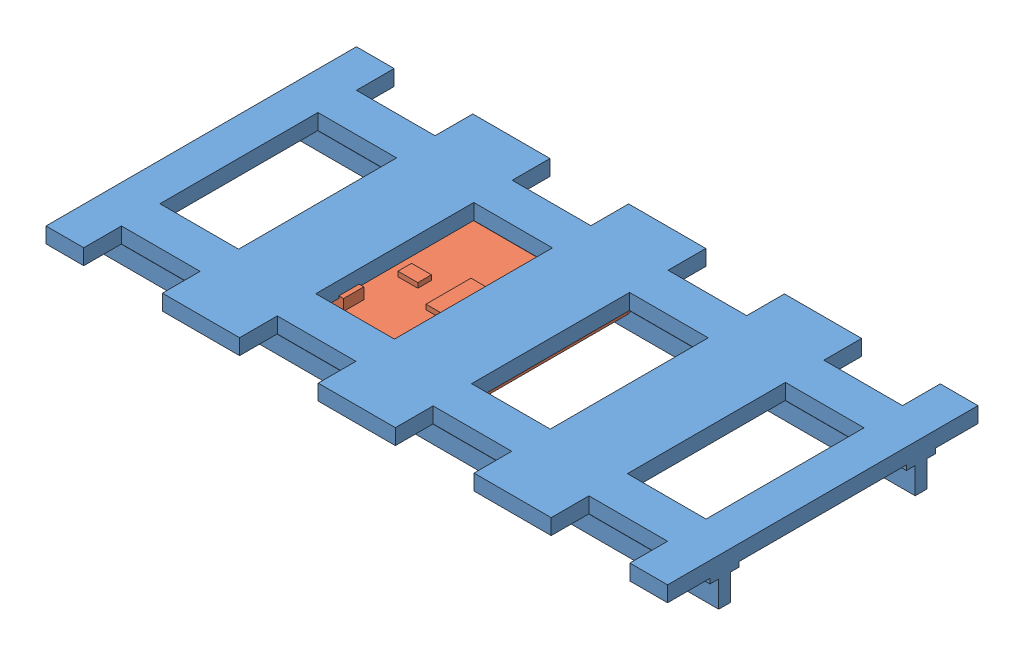
SolidWorks assembly railroad-tracks-milling-assembly, configuration Default. Lengths in mm.
Overall size (127.65 9.6 63.75).
2 component instances, 2 part files, 3 mates.
Components (placement in the parent):
- railroad-section-1: railroad-section [Default] x (1 0 0) z (0 0 -1) size (127.65 9.6 63.75)
- nfc-module-1: nfc-module [Default] at (-16 -6.2 0) size (42.85 3.45 40.6)
Mates (geometry in assembly coordinates):
- Width1: width: plane of railroad-section-1 through (7.925 -3.2 0) normal (1 0 0); plane of railroad-section-1 through (-39.925 -3.2 0) normal (-1 0 0); plane of nfc-module-1 through (5.425 -3.1903 -18.3) normal (1 0 0); plane of nfc-module-1 through (-37.425 -3.1903 -18.3) normal (-1 0 0)
- Width2: width: plane of railroad-section-1 through (0 -3.2 24.125) normal (0 0 1); plane of railroad-section-1 through (0 -3.2 -24.125) normal (0 0 -1); plane of nfc-module-1 through (-35.425 -3.1903 20.3) normal (0 0 1); plane of nfc-module-1 through (-35.425 -3.1903 -20.3) normal (0 0 -1)
- Distance1: distance = 3 mm aligned: plane of nfc-module-1 through (3.425 -6.2 18.3) normal (0 -1 0); plane of railroad-section-1 through (0 -3.2 0) normal (0 -1 0)
